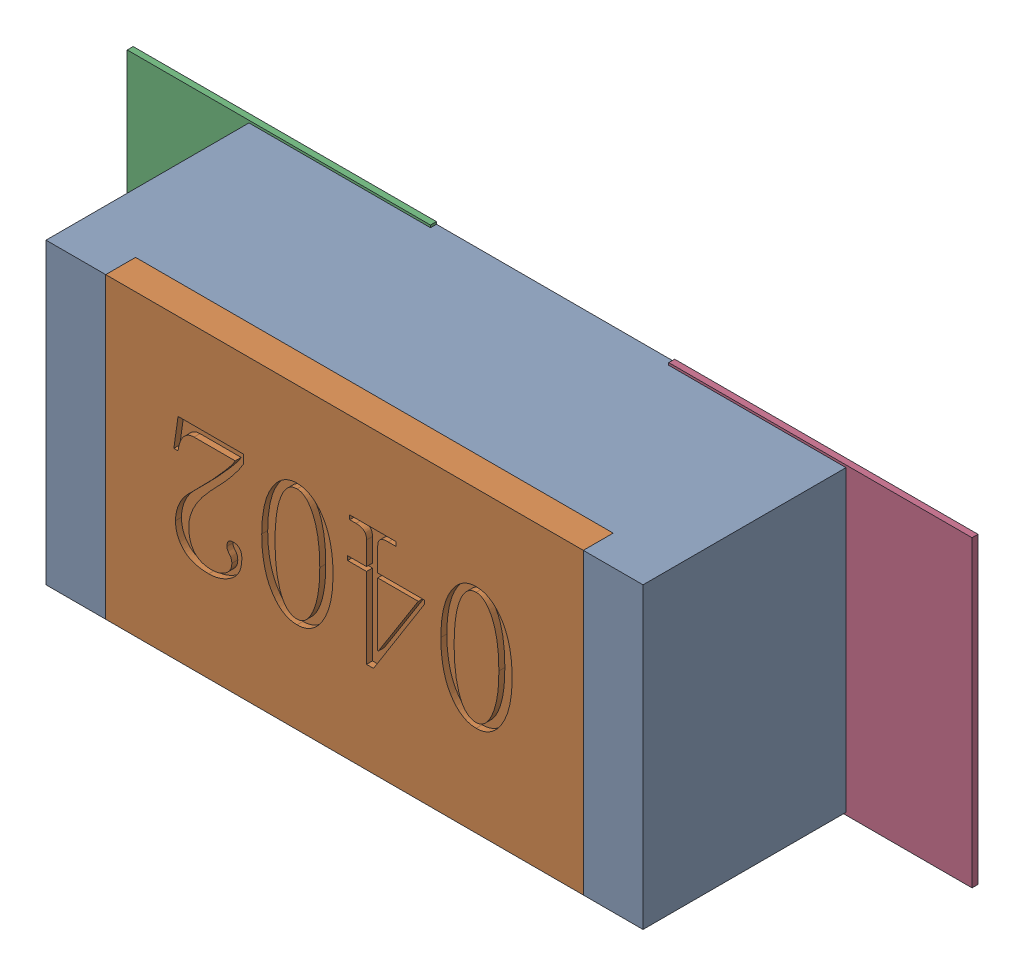
SolidWorks assembly R143, configuration Défaut. Lengths in mm.
Overall size (1.42 0.51 0.35).
5 component instances, 2 part files, 0 mates.
Components (placement in the parent):
- R0402-1: R0402 [Défaut] at (20.0335 -29.8999 0) x (-1 0 0) z (0 0 1) size (1 0.5 0.35)
- 6504207776-1: 6504207776 [Défaut] at (19.5835 -29.9001 0) size (0.51 0.51 0.01)
  - Extruded-1: Extruded [Défaut] at origin size (0.51 0.51 0.01)
- 6504207776-2: 6504207776 [Défaut] at (20.4906 -29.9001 0) size (0.51 0.51 0.01)
  - Extruded-1: Extruded [Défaut] at origin size (0.51 0.51 0.01)
